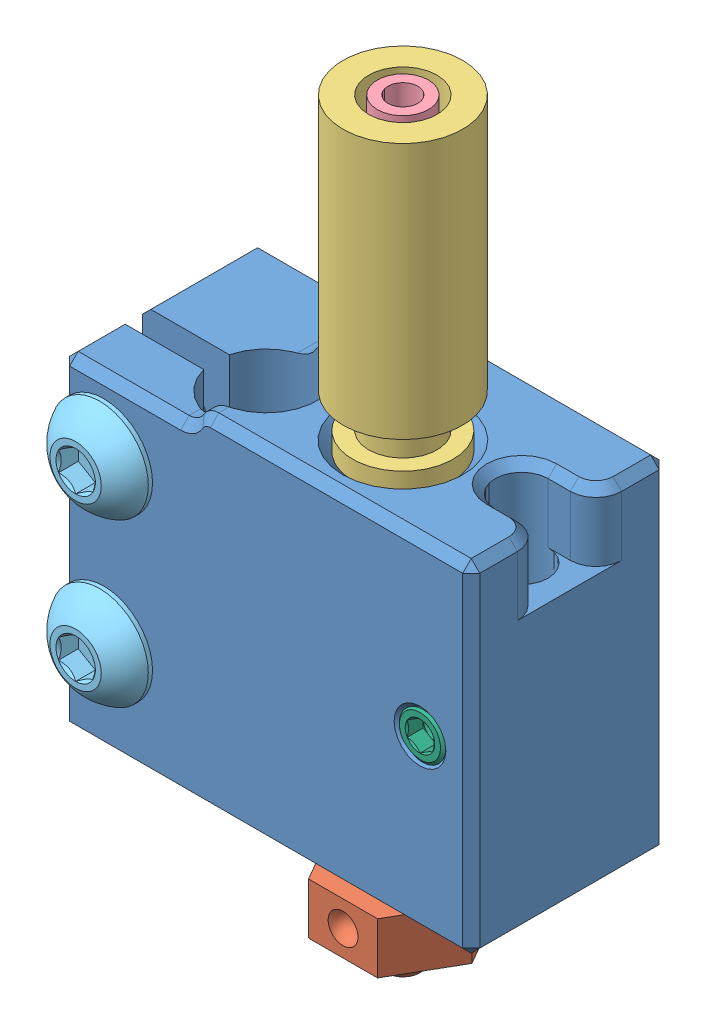
SolidWorks assembly Volcano hotend - Assemble, configuration Default. Lengths in mm.
Overall size (24.37 44 13.53).
9 component instances, 6 part files, 0 mates.
Components (placement in the parent):
- Volcano hotend-1: Volcano hotend [Default] at origin size (24 20 11.5)
- Nozzle 0.8mm-1: Nozzle 0.8mm [Default] at (0 -1.5 0) size (8.08 21 7.05)
- Throat with teflon tube_1-1: Throat with teflon tube_1 [Default] at (0 0.5 0) size (7 23 7)
  - Throat with teflon tube-1: Throat with teflon tube [Default] at origin size (7 23 7)
  - Teflon tube 1.75mm-1: Teflon tube 1.75mm [Default] at origin size (3 17 3)
- Hardware-1: Hardware [Default] at origin size (22.91 15.27 12.06)
  - M3x0.5x10 - Button Head Hex Drive Screw-1: M3x0.5x10 - Button Head Hex Drive Screw [Default] at (2.5 5.5 13.15) size (5.74 5.77 12.06)
  - M3x0.5x10 - Button Head Hex Drive Screw-2: M3x0.5x10 - Button Head Hex Drive Screw [Default] at (2.5 15 13.15) size (5.74 5.77 12.06)
  - M3x0.5x3 - Flat-Tip Set Screw-1: M3x0.5x3 - Flat-Tip Set Screw [Default] at (21 10 10) size (3.04 3.09 3.1)
